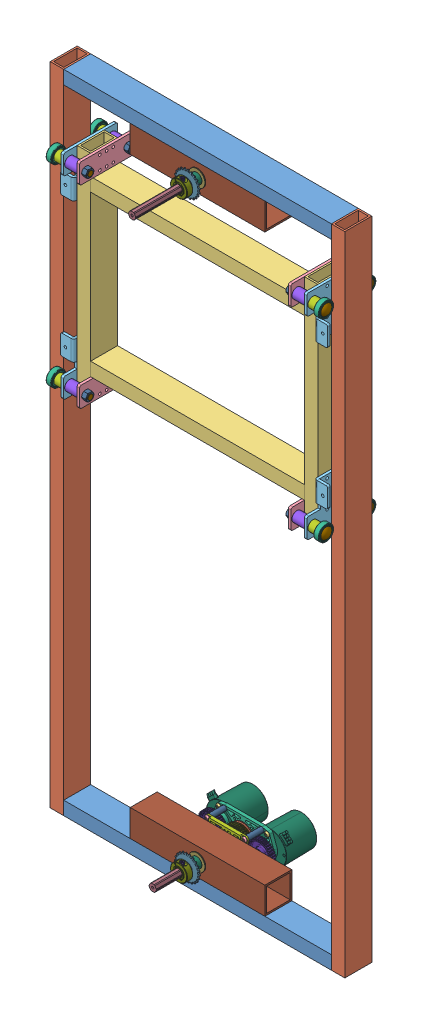
SolidWorks assembly Custom Brand New Solidwrks Assembly, configuration Default. Lengths in mm.
Overall size (835.83 1323.86 740.13).
120 component instances, 35 part files, 54 mates.
Components (placement in the parent):
- 19 and 7 8 in extrusion-1: 19 and 7 8 in extrusion [Default] at (683.3623 192.7403 428.5412) x (-1 0 0) z (0 1 0) size (504.82 50.8 25.4)
- 2 by 1 extrusion template-1: 2 by 1 extrusion template [Default] at (153.1373 167.3403 479.3412) size (25.4 1219.2 50.8)
- 2 by 1 extrusion template-2: 2 by 1 extrusion template [Default] at (683.3623 167.3403 479.3412) size (25.4 1219.2 50.8)
- 19 and 7 8 in extrusion-2: 19 and 7 8 in extrusion [Default] at (178.5373 1361.1403 428.5412) x (1 0 0) z (0 -1 0) size (504.82 50.8 25.4)
- carrige assembly-1: carrige assembly [Default] at (190.0122 1142.6943 245.5718) x (0.837169 0.457885 -0.299148) z (0.546944 -0.700852 0.457885) size (656.01 311.13 618.97)
  - 15 7 8 height-1: 15 7 8 height [Default] at (347.2127 190.7533 277.6779) x (-0.299148 0.837169 0.457885) z (-0.457885 -0.546944 0.700852) size (50.8 403.23 25.4)
  - 15 7 8 height-2: 15 7 8 height [Default] at (397.5525 225.4843 247.0662) x (-0.299148 0.837169 0.457885) z (0.837169 0 0.546944) size (50.8 403.23 25.4)
  - 15 7 8 height-3: 15 7 8 height [Default] at (38.7209 225.4843 12.6323) x (-0.299148 0.837169 0.457885) z (0.837169 0 0.546944) size (50.8 403.23 25.4)
  - 15 7 8 height-4: 15 7 8 height [Default] at (-116.834 39.6737 250.7293) x (-0.299148 0.837169 0.457885) z (0.457885 0.546944 -0.700852) size (50.8 403.23 25.4)
  - Roller-2: Roller [Défaut] at (218.0312 36.6261 530.5498) x (-0.299148 0.837169 0.457885) z (0.457885 0.546944 -0.700852) size (108.2 74.88 88.9)
    - am3793a-1: am3793a [Défaut] at (0 -30.16 0) size (101.6 4.76 38.1)
    - am3794a-1: am3794a [Défaut] at origin size (101.6 25 88.9)
    - am-0209b-1: am-0209b [Défaut] at (-39.8145 20.6375 0) x (1 0 0) z (0 1 0) size (28.57 28.57 9.53)
    - am1451-1: am1451 [Défaut] at (-39.8145 7.9375 0) x (0 0 1) z (-1 0 0) size (19.05 15.88 19.05)
    - am1451-2: am1451 [Défaut] at (39.8145 7.9375 0) x (-1 0 0) z (0 0 -1) size (19.05 15.88 19.05)
    - am-0209b-3: am-0209b [Défaut] at (39.8145 20.6375 0) x (1 0 0) z (0 1 0) size (28.57 28.57 9.53)
    - am1450-1: am1450 [Défaut] at (-39.8145 -17.46 0) size (19.05 25.4 19.05)
    - am1450-2: am1450 [Défaut] at (39.8145 -17.46 0) size (19.05 25.4 19.05)
    - round head bolt_ai-2: round head bolt_ai [RHBOLT 0.375-16x2.75x1-C] at (-39.8145 30.4292 0) x (0 -1 0) z (-1 0 0) size (74.88 20.65 20.65)
    - round head bolt_ai-3: round head bolt_ai [RHBOLT 0.375-16x2.75x1-C] at (39.8145 30.4292 0) x (0 -1 0) z (-1 0 0) size (74.88 20.65 20.65)
    - hex nut_ai-1: hex nut_ai [HNUT 0.3750-16-D-N] at (39.8145 -43.4798 0) x (0 0 1) z (0 -1 0) size (14.27 16.48 8.56)
    - hex nut_ai-2: hex nut_ai [HNUT 0.3750-16-D-N] at (-39.8145 -43.4798 0) x (0 0 1) z (0 -1 0) size (14.27 16.48 8.56)
  - Roller-3: Roller [Défaut] at (-170.0343 36.6261 277.0166) x (0.299148 -0.837169 -0.457885) z (0.457885 0.546944 -0.700852) size (108.2 74.88 88.9)
    - am3793a-1: am3793a [Défaut] at (0 -30.16 0) size (101.6 4.76 38.1)
    - am3794a-1: am3794a [Défaut] at origin size (101.6 25 88.9)
    - am-0209b-1: am-0209b [Défaut] at (-39.8145 20.6375 0) x (1 0 0) z (0 1 0) size (28.57 28.57 9.53)
    - am1451-1: am1451 [Défaut] at (-39.8145 7.9375 0) x (0 0 1) z (-1 0 0) size (19.05 15.88 19.05)
    - am1451-2: am1451 [Défaut] at (39.8145 7.9375 0) x (-1 0 0) z (0 0 -1) size (19.05 15.88 19.05)
    - am-0209b-3: am-0209b [Défaut] at (39.8145 20.6375 0) x (1 0 0) z (0 1 0) size (28.57 28.57 9.53)
    - am1450-1: am1450 [Défaut] at (-39.8145 -17.46 0) size (19.05 25.4 19.05)
    - am1450-2: am1450 [Défaut] at (39.8145 -17.46 0) size (19.05 25.4 19.05)
    - round head bolt_ai-2: round head bolt_ai [RHBOLT 0.375-16x2.75x1-C] at (-39.8145 30.4292 0) x (0 -1 0) z (-1 0 0) size (74.88 20.65 20.65)
    - round head bolt_ai-3: round head bolt_ai [RHBOLT 0.375-16x2.75x1-C] at (39.8145 30.4292 0) x (0 -1 0) z (-1 0 0) size (74.88 20.65 20.65)
    - hex nut_ai-1: hex nut_ai [HNUT 0.3750-16-D-N] at (39.8145 -43.4798 0) x (0 0 1) z (0 -1 0) size (14.27 16.48 8.56)
    - hex nut_ai-2: hex nut_ai [HNUT 0.3750-16-D-N] at (-39.8145 -43.4798 0) x (0 0 1) z (0 -1 0) size (14.27 16.48 8.56)
  - Roller-4: Roller [Défaut] at (385.2164 236.3291 274.6512) x (0.299148 -0.837169 -0.457885) z (-0.457885 -0.546944 0.700852) size (108.2 74.88 88.9)
    - am3793a-1: am3793a [Défaut] at (0 -30.16 0) size (101.6 4.76 38.1)
    - am3794a-1: am3794a [Défaut] at origin size (101.6 25 88.9)
    - am-0209b-1: am-0209b [Défaut] at (-39.8145 20.6375 0) x (1 0 0) z (0 1 0) size (28.57 28.57 9.53)
    - am1451-1: am1451 [Défaut] at (-39.8145 7.9375 0) x (0 0 1) z (-1 0 0) size (19.05 15.88 19.05)
    - am1451-2: am1451 [Défaut] at (39.8145 7.9375 0) x (-1 0 0) z (0 0 -1) size (19.05 15.88 19.05)
    - am-0209b-3: am-0209b [Défaut] at (39.8145 20.6375 0) x (1 0 0) z (0 1 0) size (28.57 28.57 9.53)
    - am1450-1: am1450 [Défaut] at (-39.8145 -17.46 0) size (19.05 25.4 19.05)
    - am1450-2: am1450 [Défaut] at (39.8145 -17.46 0) size (19.05 25.4 19.05)
    - round head bolt_ai-2: round head bolt_ai [RHBOLT 0.375-16x2.75x1-C] at (-39.8145 30.4292 0) x (0 -1 0) z (-1 0 0) size (74.88 20.65 20.65)
    - round head bolt_ai-3: round head bolt_ai [RHBOLT 0.375-16x2.75x1-C] at (39.8145 30.4292 0) x (0 -1 0) z (-1 0 0) size (74.88 20.65 20.65)
    - hex nut_ai-1: hex nut_ai [HNUT 0.3750-16-D-N] at (39.8145 -43.4798 0) x (0 0 1) z (0 -1 0) size (14.27 16.48 8.56)
    - hex nut_ai-2: hex nut_ai [HNUT 0.3750-16-D-N] at (-39.8145 -43.4798 0) x (0 0 1) z (0 -1 0) size (14.27 16.48 8.56)
  - Roller-5: Roller [Défaut] at (-2.8492 236.3291 21.1179) x (-0.299148 0.837169 0.457885) z (-0.457885 -0.546944 0.700852) size (108.2 74.88 88.9)
    - am3793a-1: am3793a [Défaut] at (0 -30.16 0) size (101.6 4.76 38.1)
    - am3794a-1: am3794a [Défaut] at origin size (101.6 25 88.9)
    - am-0209b-1: am-0209b [Défaut] at (-39.8145 20.6375 0) x (1 0 0) z (0 1 0) size (28.57 28.57 9.53)
    - am1451-1: am1451 [Défaut] at (-39.8145 7.9375 0) x (0 0 1) z (-1 0 0) size (19.05 15.88 19.05)
    - am1451-2: am1451 [Défaut] at (39.8145 7.9375 0) x (-1 0 0) z (0 0 -1) size (19.05 15.88 19.05)
    - am-0209b-3: am-0209b [Défaut] at (39.8145 20.6375 0) x (1 0 0) z (0 1 0) size (28.57 28.57 9.53)
    - am1450-1: am1450 [Défaut] at (-39.8145 -17.46 0) size (19.05 25.4 19.05)
    - am1450-2: am1450 [Défaut] at (39.8145 -17.46 0) size (19.05 25.4 19.05)
    - round head bolt_ai-2: round head bolt_ai [RHBOLT 0.375-16x2.75x1-C] at (-39.8145 30.4292 0) x (0 -1 0) z (-1 0 0) size (74.88 20.65 20.65)
    - round head bolt_ai-3: round head bolt_ai [RHBOLT 0.375-16x2.75x1-C] at (39.8145 30.4292 0) x (0 -1 0) z (-1 0 0) size (74.88 20.65 20.65)
    - hex nut_ai-1: hex nut_ai [HNUT 0.3750-16-D-N] at (39.8145 -43.4798 0) x (0 0 1) z (0 -1 0) size (14.27 16.48 8.56)
    - hex nut_ai-2: hex nut_ai [HNUT 0.3750-16-D-N] at (-39.8145 -43.4798 0) x (0 0 1) z (0 -1 0) size (14.27 16.48 8.56)
- REV-21-2099 1-to-1-1: REV-21-2099 1-to-1 [Default] at (430.9382 218.1403 387.2662) x (0 0 1) z (-1 0 0) size (99.54 69.01 161.62)
  - REV-21-2099 1-to-1.STEP-1: REV-21-2099 1-to-1.STEP [Default] at origin size (99.54 69.01 161.62)
    - REV-21-1879_For Motor Shaft, One Clip (Spaced 0.150).STEP-1: REV-21-1879_For Motor Shaft, One Clip (Spaced 0.150).STEP [Default] at (3.5 0 45.72) x (0 0 -1) z (1 0 0) size (13 13.75 24.57)
      - REV-21-1879.STEP-1: REV-21-1879.STEP [Default] at origin size (12.7 13.75 20)
      - Key_2mm_20mmLong.STEP-1: Key_2mm_20mmLong.STEP [Default] at (0.0325 4.05 10) x (0 0 -1) z (0 1 0) size (20 2 2)
      - Retaining_Ring_8mm.STEP-1: Retaining_Ring_8mm.STEP [Default] at (0 0 24.185) x (-1 0 0) z (0 0 1) size (13 13 0.76)
    - REV-21-1879_For Motor Shaft, One Clip (Spaced 0.150).STEP-2: REV-21-1879_For Motor Shaft, One Clip (Spaced 0.150).STEP [Default] at (3.5 0 -45.72) x (0 -1 0) z (1 0 0) size (13 13.75 24.57)
      - REV-21-1879.STEP-1: REV-21-1879.STEP [Default] at origin size (12.7 13.75 20)
      - Key_2mm_20mmLong.STEP-1: Key_2mm_20mmLong.STEP [Default] at (0.0325 4.05 10) x (0 0 -1) z (0 1 0) size (20 2 2)
      - Retaining_Ring_8mm.STEP-1: Retaining_Ring_8mm.STEP [Default] at (0 0 24.185) x (-1 0 0) z (0 0 1) size (13 13 0.76)
    - REV-21-2079.STEP-1: REV-21-2079.STEP [Default] at (20.6375 0 0) size (41.27 34.92 32.55)
    - REV-21-1650.STEP-1: REV-21-1650.STEP [Default] at (0 0 -45.72) x (0 -1 0) z (1 0 0) size (65.4 64.76 93.26)
    - REV-21-1650.STEP-2: REV-21-1650.STEP [Default] at (0 0 45.72) x (0 0 -1) z (1 0 0) size (65.4 64.76 93.26)
    - REV-21-3012.STEP-1: REV-21-3012.STEP [Default] at (17.375 0 0) x (0 1 0) z (1 0 0) size (48.1 48.1 12.7)
    - REV-21-1929.STEP-1: REV-21-1929.STEP [Default] at (17.7875 0 45.72) x (0 0 1) z (-1 0 0) size (48.2 48.2 12.7)
    - REV-21-1929.STEP-2: REV-21-1929.STEP [Default] at (17.7875 0 -45.72) x (0 -0.5 0.866025) z (-1 0 0) size (48.2 48.2 12.7)
    - REV-21-2541.STEP-1: REV-21-2541.STEP [Default] at (9.4375 0 0) x (0 0 -1) z (1 0 0) size (38.1 38.1 3.17)
    - REV-21-2541.STEP-2: REV-21-2541.STEP [Default] at (25.4875 0 0) x (0 0 -1) z (1 0 0) size (38.1 38.1 3.17)
    - REV-21-2542.STEP-1: REV-21-2542.STEP [Default] at (30.25 0 0) x (0 0 1) z (-1 0 0) size (38.1 38.1 6.35)
    - F6806ZZ.STEP-1: F6806ZZ.STEP [Default] at (4.35 0 0) x (0 -0.419542 0.907736) z (-1 0 0) size (45 45 7)
    - F6806ZZ.STEP-2: F6806ZZ.STEP [Default] at (36.925 0 0) x (0 -0.734429 0.678686) z (1 0 0) size (45 45 7)
    - #10 Button Head Cap Screws_0.500 Long.STEP-1: #10 Button Head Cap Screws_0.500 Long.STEP [Default] at (1.2827 25.4 45.72) x (0 0.07794 -0.996958) z (1 0 0) size (9.17 9.17 15.27)
    - #10 Button Head Cap Screws_0.500 Long.STEP-2: #10 Button Head Cap Screws_0.500 Long.STEP [Default] at (1.2827 -25.4 45.72) x (0 0.235024 -0.971989) z (1 0 0) size (9.17 9.17 15.27)
    - #10 Button Head Cap Screws_0.500 Long.STEP-3: #10 Button Head Cap Screws_0.500 Long.STEP [Default] at (1.2827 25.4 -45.72) x (0 0.356877 -0.934151) z (1 0 0) size (9.17 9.17 15.27)
    - #10 Button Head Cap Screws_0.500 Long.STEP-4: #10 Button Head Cap Screws_0.500 Long.STEP [Default] at (1.2827 -25.4 -45.72) x (0 0.442397 -0.896819) z (1 0 0) size (9.17 9.17 15.27)
    - #10 Button Head Cap Screws_1.500 Long.STEP-1: #10 Button Head Cap Screws_1.500 Long.STEP [Default] at (20.3327 27.454 35.2002) x (0 -0.07794 0.996958) z (1 0 0) size (9.17 9.17 40.67)
    - #10 Button Head Cap Screws_1.500 Long.STEP-2: #10 Button Head Cap Screws_1.500 Long.STEP [Default] at (20.3327 27.454 -35.2002) x (0 -0.235024 0.971989) z (1 0 0) size (9.17 9.17 40.67)
    - #10 Button Head Cap Screws_1.500 Long.STEP-3: #10 Button Head Cap Screws_1.500 Long.STEP [Default] at (20.3327 -27.454 -35.2002) x (0 -0.356877 0.934151) z (1 0 0) size (9.17 9.17 40.67)
    - #10 Button Head Cap Screws_1.500 Long.STEP-4: #10 Button Head Cap Screws_1.500 Long.STEP [Default] at (20.3327 -27.454 35.2002) x (0 -0.442397 0.896819) z (1 0 0) size (9.17 9.17 40.67)
    - REV-21-2078.STEP-1: REV-21-2078.STEP [Default] at (25.725 0 45.72) x (0 0 1) z (-1 0 0) size (14.29 14.29 3.17)
    - REV-21-2078.STEP-2: REV-21-2078.STEP [Default] at (25.725 0 -45.72) x (0 1 0) z (-1 0 0) size (14.29 14.29 3.17)
    - REV-21-2099-P01.STEP-1: REV-21-2099-P01.STEP [Default] at origin size (6.35 64.43 118.43)
    - REV-21-2099-P02.STEP-1: REV-21-2099-P02.STEP [Default] at (34.925 0 0) size (6.35 64.43 79.93)
    - REV-21-2005.STEP-1: REV-21-2005.STEP [Default] at (6.675 0 45.72) x (0 0 -1) z (1 0 0) size (18.29 18.29 6.35)
    - REV-21-2003.STEP-1: REV-21-2003.STEP [Default] at (10.6438 0 45.72) x (0 0 -1) z (1 0 0) size (18.29 18.29 1.59)
    - REV-21-2003.STEP-2: REV-21-2003.STEP [Default] at (10.6438 0 -45.72) x (0 0 -1) z (1 0 0) size (18.29 18.29 1.59)
    - REV-21-2005.STEP-2: REV-21-2005.STEP [Default] at (6.675 0 -45.72) x (0 0 -1) z (1 0 0) size (18.29 18.29 6.35)
    - #10 Unthreaded Spacers_1.125in Long.STEP-1: #10 Unthreaded Spacers_1.125in Long.STEP [Default] at (20.6375 27.454 35.2002) size (28.57 9.53 9.53)
    - #10 Unthreaded Spacers_1.125in Long.STEP-2: #10 Unthreaded Spacers_1.125in Long.STEP [Default] at (20.6375 -27.454 35.2002) size (28.57 9.53 9.53)
    - #10 Unthreaded Spacers_1.125in Long.STEP-3: #10 Unthreaded Spacers_1.125in Long.STEP [Default] at (20.6375 27.454 -35.2002) size (28.57 9.53 9.53)
    - #10 Unthreaded Spacers_1.125in Long.STEP-4: #10 Unthreaded Spacers_1.125in Long.STEP [Default] at (20.6375 -27.454 -35.2002) size (28.57 9.53 9.53)
- Elevator Attachment-1: Elevator Attachment [Default] at (303.9498 243.5403 479.3412) x (1 0 0) z (0 1 0) size (254 50.8 50.8)
- Half inch flange bearing.step-1: Half inch flange bearing.step [Default] at (430.9498 218.1403 434.9445) x (-0.999907 -0.013661 0) z (0 0 -1) size (31.12 31.12 7.93)
- Half inch flange bearing.step-2: Half inch flange bearing.step [Default] at (430.9498 218.1403 472.9378) size (31.12 31.12 7.93)
- REV-half inch Hex Shaft 6.92 in-1: REV-half inch Hex Shaft 6.92 in [Default] at (430.9411 218.1453 845.3162) x (0.866025 -0.5 0) z (0 0 1) size (12.69 13.74 175.77)
- WCP-0560 Rev1.step-1: WCP-0560 Rev1.step [Default] at (430.9587 218.1149 498.3277) x (0.866025 0.5 0) z (0 0 1) size (47.96 47.68 9.53)
- WCP-0790_500L_500_hex.step-1: WCP-0790_500L_500_hex.step [Default] at (430.8649 218.0133 487.2152) x (-1 0 0) z (0 0 -1) size (19.5 19.5 12.7)
- Elevator Attachment-3: Elevator Attachment [Default] at (303.9498 1310.3403 479.3412) size (254 50.8 50.8)
- Half inch flange bearing.step-3: Half inch flange bearing.step [Default] at (430.9498 1335.7403 434.9445) x (-1 0 0) z (0 0 -1) size (31.12 31.12 7.93)
- Half inch flange bearing.step-4: Half inch flange bearing.step [Default] at (430.9498 1335.7403 472.9378) x (0.540386 0.841418 0) z (0 0 1) size (31.12 31.12 7.93)
- WCP-0560 Rev1.step-2: WCP-0560 Rev1.step [Default] at (430.9601 1335.7094 498.3277) x (-0.047279 -0.998882 0) z (0 0 1) size (47.96 47.68 9.53)
- REV-half inch Hex Shaft 6.92 in-2: REV-half inch Hex Shaft 6.92 in [Default] at (430.944 1335.7406 145.5852) x (-0.047279 -0.998882 0) z (0 0 -1) size (12.69 13.74 175.77)
- WCP-0790_500L_500_hex.step-2: WCP-0790_500L_500_hex.step [Default] at (431.0139 1335.6051 487.2152) x (-0.998882 0.047279 0) z (0 0 -1) size (19.5 19.5 12.7)
- am-1526 500Hex HD Collar Clamp.STEP-1: am-1526 500Hex HD Collar Clamp.STEP [Default] at (370.6257 292.0106 548.8001) x (-0.5 0.866025 0) z (0 0 -1) size (31.73 31.75 12.7)
  - am-1238a 500Hex Collar Clamp Body.STEP-1: am-1238a 500Hex Collar Clamp Body.STEP [Default] at (-94.2794 15.3021 33.01) size (31.73 31.75 12.7)
  - 10-32x0500_shcs_HX-SHCS 0.19-32x1.375x1-C.STEP-1: 10-32x0500_shcs_HX-SHCS 0.19-32x1.375x1-C.STEP [Default] at (-83.1669 24.154 39.36) x (0 -1 0) z (0 0 1) size (17.53 7.94 7.94)
- am-1526 500Hex HD Collar Clamp.STEP-2: am-1526 500Hex HD Collar Clamp.STEP [Default] at (374.1883 1412.3749 548.8001) x (-0.458496 0.888696 0) z (0 0 -1) size (31.73 31.75 12.7)
  - am-1238a 500Hex Collar Clamp Body.STEP-1: am-1238a 500Hex Collar Clamp Body.STEP [Default] at (-94.2794 15.3021 33.01) size (31.73 31.75 12.7)
  - 10-32x0500_shcs_HX-SHCS 0.19-32x1.375x1-C.STEP-1: 10-32x0500_shcs_HX-SHCS 0.19-32x1.375x1-C.STEP [Default] at (-83.1669 24.154 39.36) x (0 -1 0) z (0 0 1) size (17.53 7.94 7.94)
Mates (geometry in assembly coordinates):
- Coincident2: coincident aligned: plane of 19 and 7 8 in extrusion-1 through (178.5373 192.7403 479.3412) normal (0 0 1); plane of 2 by 1 extrusion template-2 through (683.3623 1386.5403 479.3412) normal (0 0 1)
- Coincident3: coincident aligned: plane of 19 and 7 8 in extrusion-1 through (178.5373 167.3403 428.5412) normal (0 -1 0); plane of 2 by 1 extrusion template-2 through (683.3623 167.3403 479.3412) normal (0 -1 0)
- Coincident4: coincident anti-aligned: plane of 19 and 7 8 in extrusion-1 through (683.3623 192.7403 428.5412) normal (1 0 0); plane of 2 by 1 extrusion template-2 through (683.3623 1386.5403 479.3412) normal (-1 0 0)
- Coincident5: coincident: plane of 19 and 7 8 in extrusion-1 through (178.5373 192.7403 479.3412) normal (0 0 1); plane of 2 by 1 extrusion template-1 through (153.1373 1386.5403 479.3412) normal (0 0 1)
- Coincident6: coincident: plane of 19 and 7 8 in extrusion-1 through (178.5373 167.3403 428.5412) normal (0 -1 0); plane of 2 by 1 extrusion template-1 through (153.1373 167.3403 479.3412) normal (0 -1 0)
- Coincident7: coincident anti-aligned: plane of 19 and 7 8 in extrusion-1 through (178.5373 192.7403 428.5412) normal (-1 0 0); plane of 2 by 1 extrusion template-1 through (178.5373 1386.5403 479.3412) normal (1 0 0)
- Coincident8: coincident anti-aligned: plane of 2 by 1 extrusion template-1 through (178.5373 1386.5403 479.3412) normal (1 0 0); plane of 19 and 7 8 in extrusion-2 through (178.5373 1361.1403 428.5412) normal (-1 0 0)
- Coincident9: coincident aligned: plane of 2 by 1 extrusion template-1 through (153.1373 1386.5403 428.5412) normal (0 0 -1); plane of 19 and 7 8 in extrusion-2 through (683.3623 1361.1403 428.5412) normal (0 0 -1)
- Coincident10: coincident aligned: plane of 2 by 1 extrusion template-2 through (683.3623 1386.5403 479.3412) normal (0 1 0); plane of 19 and 7 8 in extrusion-2 through (683.3623 1386.5403 428.5412) normal (0 1 0)
- Coincident12: coincident aligned: plane of 2 by 1 extrusion template-2 through (683.3623 1386.5403 428.5412) normal (0 0 -1); plane of carrige assembly-1/15 7 8 height-2 through (657.9623 871.673 428.5412) normal (0 0 -1)
- Width1: width aligned: plane of 2 by 1 extrusion template-2 through (683.3623 1386.5403 428.5412) normal (0 0 -1); plane of carrige assembly-1/15 7 8 height-2 through (153.1373 1386.5403 428.5412) normal (0 0 -1); plane of 2 by 1 extrusion template-1 through (657.9623 871.673 428.5412) normal (0 0 -1); plane of carrige assembly-1/15 7 8 height-3 through (229.3373 871.673 428.5412) normal (0 0 -1)
- Width2: width anti-aligned: plane of 2 by 1 extrusion template-2 through (683.3623 1386.5403 479.3412) normal (-1 0 0); plane of carrige assembly-1/15 7 8 height-2 through (178.5373 1386.5403 479.3412) normal (1 0 0); plane of 2 by 1 extrusion template-1 through (657.9623 871.673 428.5412) normal (1 0 0); plane of carrige assembly-1/15 7 8 height-3 through (203.9373 871.673 428.5412) normal (-1 0 0)
- Coincident13: coincident anti-aligned: plane of 19 and 7 8 in extrusion-1 through (178.5373 192.7403 428.5412) normal (0 1 0); plane of Elevator Attachment-1 through (557.9498 192.7403 479.3412) normal (0 -1 0)
- Coincident14: coincident aligned: plane of 19 and 7 8 in extrusion-1 through (178.5373 192.7403 428.5412) normal (0 0 -1); plane of Elevator Attachment-1 through (557.9498 243.5403 428.5412) normal (0 0 -1)
- Width3: width aligned: plane of 2 by 1 extrusion template-1 through (178.5373 1386.5403 479.3412) normal (1 0 0); plane of Elevator Attachment-1 through (683.3623 1386.5403 479.3412) normal (-1 0 0); plane of 2 by 1 extrusion template-2 through (557.9498 243.5403 479.3412) normal (1 0 0); plane of Elevator Attachment-1 through (303.9498 243.5403 479.3412) normal (-1 0 0)
- Coincident16: coincident anti-aligned: plane of Elevator Attachment-1 through (557.9498 243.5403 428.5412) normal (0 0 -1); plane of Half inch flange bearing.step-1 through (416.9811 217.9495 428.5412) normal (0 0 1)
- Concentric2: concentric aligned: cylinder of Elevator Attachment-1 through (430.9498 218.1403 83.8784) axis (0 0 1) radius 12.7; cylinder of Half inch flange bearing.step-1 through (430.9498 218.1403 427.0172) axis (0 0 1) radius 14.2875
- Concentric3: concentric anti-aligned: cylinder of Elevator Attachment-1 through (430.9498 218.1403 83.8784) axis (0 0 1) radius 12.7; cylinder of Half inch flange bearing.step-2 through (430.9498 218.1403 480.8652) axis (0 0 -1) radius 14.2875
- Coincident17: coincident anti-aligned: plane of Elevator Attachment-1 through (557.9498 243.5403 479.3412) normal (0 0 1); plane of Half inch flange bearing.step-2 through (444.9198 218.1403 479.3412) normal (0 0 -1)
- Coincident18: coincident anti-aligned: plane of REV-21-2099 1-to-1-1/REV-21-2099 1-to-1.STEP-1/REV-21-2099-P02.STEP-1 through (430.9382 218.1403 428.5412) normal (0 0 1); plane of Elevator Attachment-1 through (557.9498 243.5403 428.5412) normal (0 0 -1)
- Coincident19: coincident aligned: plane of REV-21-2099 1-to-1-1/REV-21-2099 1-to-1.STEP-1/REV-21-2079.STEP-1 through (425.8885 224.5613 388.1162) normal (0 0 -1); plane of REV-half inch Hex Shaft 6.92 in-1 through (430.9411 218.1453 388.1162) normal (0 0 -1)
- Coincident20: coincident anti-aligned: plane of REV-21-2099 1-to-1-1/REV-21-2099 1-to-1.STEP-1/REV-21-2079.STEP-1 through (438.2706 218.1403 387.2662) normal (-0.866025 -0.5 0); plane of REV-half inch Hex Shaft 6.92 in-1 through (436.4361 221.3178 1302.5162) normal (0.866025 0.5 0)
- Coincident21: coincident anti-aligned: plane of REV-21-2099 1-to-1-1/REV-21-2099 1-to-1.STEP-1/REV-21-2079.STEP-1 through (434.6044 224.4903 387.2662) normal (0 -1 0); plane of REV-half inch Hex Shaft 6.92 in-1 through (430.9411 224.4903 1302.5162) normal (0 1 0)
- Coincident23: coincident anti-aligned: plane of Half inch flange bearing.step-2 through (427.2836 224.4903 480.8652) normal (0 -1 0); plane of REV-half inch Hex Shaft 6.92 in-1 through (430.9411 224.4903 1302.5162) normal (0 1 0)
- Coincident24: coincident anti-aligned: plane of Half inch flange bearing.step-2 through (427.2836 211.7903 480.8652) normal (0.866025 0.5 0); plane of REV-half inch Hex Shaft 6.92 in-1 through (425.4462 214.9728 1302.5162) normal (-0.866025 -0.5 0)
- Parallel1: parallel aligned: plane of 19 and 7 8 in extrusion-1 through (178.5373 167.3403 428.5412) normal (0 -1 0); plane of REV-21-2099 1-to-1-1/REV-21-2099 1-to-1.STEP-1/REV-21-2099-P02.STEP-1 through (430.9382 185.9238 428.5412) normal (0 -1 0)
- Coincident42: coincident anti-aligned: plane of REV-half inch Hex Shaft 6.92 in-1 through (430.9411 224.4903 1302.5162) normal (0 1 0); plane of WCP-0790_500L_500_hex.step-1 through (427.1254 224.4903 480.8652) normal (0 -1 0)
- Coincident43: coincident anti-aligned: plane of REV-half inch Hex Shaft 6.92 in-1 through (436.4361 221.3178 1302.5162) normal (0.866025 0.5 0); plane of WCP-0790_500L_500_hex.step-1 through (434.6044 224.4903 480.8652) normal (-0.866025 -0.5 0)
- Coincident44: coincident anti-aligned: plane of Half inch flange bearing.step-2 through (446.5073 218.1403 480.8652) normal (0 0 1); plane of WCP-0790_500L_500_hex.step-1 through (430.8649 218.0133 480.8652) normal (0 0 -1)
- Coincident45: coincident anti-aligned: plane of REV-half inch Hex Shaft 6.92 in-1 through (425.4462 221.3178 1302.5162) normal (-0.866025 0.5 0); plane of WCP-0560 Rev1.step-1 through (427.2778 224.4903 493.5652) normal (0.866025 -0.5 0)
- Coincident46: coincident anti-aligned: plane of REV-half inch Hex Shaft 6.92 in-1 through (430.9411 224.4903 1302.5162) normal (0 1 0); plane of WCP-0560 Rev1.step-1 through (434.6395 224.4903 493.5652) normal (0 -1 0)
- Coincident47: coincident anti-aligned: plane of WCP-0560 Rev1.step-1 through (430.9587 218.1149 493.5652) normal (0 0 -1); plane of WCP-0790_500L_500_hex.step-1 through (430.8649 218.0133 493.5652) normal (0 0 1)
- Coincident48: coincident anti-aligned: plane of 19 and 7 8 in extrusion-2 through (683.3623 1361.1403 428.5412) normal (0 -1 0); plane of Elevator Attachment-3 through (557.9498 1361.1403 479.3412) normal (0 1 0)
- Coincident49: coincident aligned: plane of 19 and 7 8 in extrusion-2 through (683.3623 1361.1403 428.5412) normal (0 0 -1); plane of Elevator Attachment-3 through (557.9498 1310.3403 428.5412) normal (0 0 -1)
- Width6: width anti-aligned: plane of 2 by 1 extrusion template-1 through (178.5373 1386.5403 479.3412) normal (1 0 0); plane of Elevator Attachment-3 through (683.3623 1386.5403 479.3412) normal (-1 0 0); plane of 2 by 1 extrusion template-2 through (303.9498 1310.3403 479.3412) normal (-1 0 0); plane of Elevator Attachment-3 through (557.9498 1310.3403 479.3412) normal (1 0 0)
- Coincident50: coincident anti-aligned: plane of Elevator Attachment-3 through (557.9498 1310.3403 428.5412) normal (0 0 -1); plane of Half inch flange bearing.step-3 through (416.9798 1335.7403 428.5412) normal (0 0 1)
- Concentric4: concentric anti-aligned: cylinder of Elevator Attachment-3 through (430.9498 1335.7403 824.0039) axis (0 0 -1) radius 12.7; cylinder of Half inch flange bearing.step-3 through (430.9498 1335.7403 427.0172) axis (0 0 1) radius 14.2875
- Coincident51: coincident anti-aligned: plane of Elevator Attachment-3 through (557.9498 1310.3403 479.3412) normal (0 0 1); plane of Half inch flange bearing.step-4 through (438.499 1347.4949 479.3412) normal (0 0 -1)
- Concentric5: concentric aligned: cylinder of Elevator Attachment-3 through (430.9498 1335.7403 824.0039) axis (0 0 -1) radius 12.7; cylinder of Half inch flange bearing.step-4 through (430.9498 1335.7403 480.8652) axis (0 0 -1) radius 14.2875
- Distance1: distance = 0 mm aligned: plane of REV-half inch Hex Shaft 6.92 in-2 through (428.6501 1287.2759 427.0172) normal (0 0 -1); plane of Half inch flange bearing.step-3 through (415.3923 1335.7403 427.0172) normal (0 0 -1)
- Coincident53: coincident anti-aligned: plane of Half inch flange bearing.step-4 through (426.9875 1329.5708 480.8652) normal (0.888696 0.458496 0); plane of REV-half inch Hex Shaft 6.92 in-2 through (425.3052 1332.8314 -311.6148) normal (-0.888696 -0.458496 0)
- Coincident54: coincident anti-aligned: plane of Half inch flange bearing.step-4 through (423.6256 1336.087 480.8652) normal (0.841418 -0.540386 0); plane of REV-half inch Hex Shaft 6.92 in-2 through (425.6052 1339.1693 -311.6148) normal (-0.841418 0.540386 0)
- Coincident55: coincident anti-aligned: plane of Half inch flange bearing.step-4 through (439.3568 1348.8307 480.8652) normal (0 0 1); plane of WCP-0790_500L_500_hex.step-2 through (431.0139 1335.6051 480.8652) normal (0 0 -1)
- Coincident56: coincident anti-aligned: plane of REV-half inch Hex Shaft 6.92 in-2 through (431.244 1342.0785 -311.6148) normal (0.047279 0.998882 0); plane of WCP-0790_500L_500_hex.step-2 through (427.5848 1342.2517 480.8652) normal (-0.047279 -0.998882 0)
- Coincident57: coincident anti-aligned: plane of REV-half inch Hex Shaft 6.92 in-2 through (425.6052 1339.1693 -311.6148) normal (-0.841418 0.540386 0); plane of WCP-0790_500L_500_hex.step-2 through (423.5433 1335.9587 480.8652) normal (0.841418 -0.540386 0)
- Coincident58: coincident anti-aligned: plane of WCP-0560 Rev1.step-2 through (430.9601 1335.7094 493.5652) normal (0 0 -1); plane of WCP-0790_500L_500_hex.step-2 through (431.0139 1335.6051 493.5652) normal (0 0 1)
- Coincident59: coincident anti-aligned: plane of WCP-0560 Rev1.step-2 through (434.9383 1341.9036 493.5652) normal (-0.047279 -0.998882 0); plane of REV-half inch Hex Shaft 6.92 in-2 through (431.244 1342.0785 -311.6148) normal (0.047279 0.998882 0)
- Coincident60: coincident anti-aligned: plane of WCP-0560 Rev1.step-2 through (427.5848 1342.2517 493.5652) normal (0.841418 -0.540386 0); plane of REV-half inch Hex Shaft 6.92 in-2 through (425.6052 1339.1693 -311.6148) normal (-0.841418 0.540386 0)
- Coincident61: coincident anti-aligned: plane of WCP-0560 Rev1.step-1 through (430.9587 218.1149 503.0902) normal (0 0 1); plane of am-1526 500Hex HD Collar Clamp.STEP-1/am-1238a 500Hex Collar Clamp Body.STEP-1 through (431.0173 218.0133 503.0902) normal (0 0 -1)
- Coincident62: coincident anti-aligned: plane of REV-half inch Hex Shaft 6.92 in-1 through (430.9411 224.4903 1302.5162) normal (0 1 0); plane of am-1526 500Hex HD Collar Clamp.STEP-1/am-1238a 500Hex Collar Clamp Body.STEP-1 through (427.2778 224.4903 515.7902) normal (0 -1 0)
- Coincident63: coincident anti-aligned: plane of REV-half inch Hex Shaft 6.92 in-1 through (425.4462 221.3178 1302.5162) normal (-0.866025 0.5 0); plane of am-1526 500Hex HD Collar Clamp.STEP-1/am-1238a 500Hex Collar Clamp Body.STEP-1 through (423.5383 218.0133 515.7902) normal (0.866025 -0.5 0)
- Coincident64: coincident anti-aligned: plane of WCP-0560 Rev1.step-2 through (430.9601 1335.7094 503.0902) normal (0 0 1); plane of am-1526 500Hex HD Collar Clamp.STEP-2/am-1238a 500Hex Collar Clamp Body.STEP-1 through (427.4947 1330.1255 503.0902) normal (0 0 -1)
- Coincident65: coincident anti-aligned: plane of REV-half inch Hex Shaft 6.92 in-2 through (431.244 1342.0785 -311.6148) normal (0.047279 0.998882 0); plane of am-1526 500Hex HD Collar Clamp.STEP-2/am-1238a 500Hex Collar Clamp Body.STEP-1 through (424.0656 1336.772 515.7902) normal (-0.047279 -0.998882 0)
- Coincident66: coincident anti-aligned: plane of REV-half inch Hex Shaft 6.92 in-2 through (425.6052 1339.1693 -311.6148) normal (-0.841418 0.540386 0); plane of am-1526 500Hex HD Collar Clamp.STEP-2/am-1238a 500Hex Collar Clamp Body.STEP-1 through (420.024 1330.4791 515.7902) normal (0.841418 -0.540386 0)
